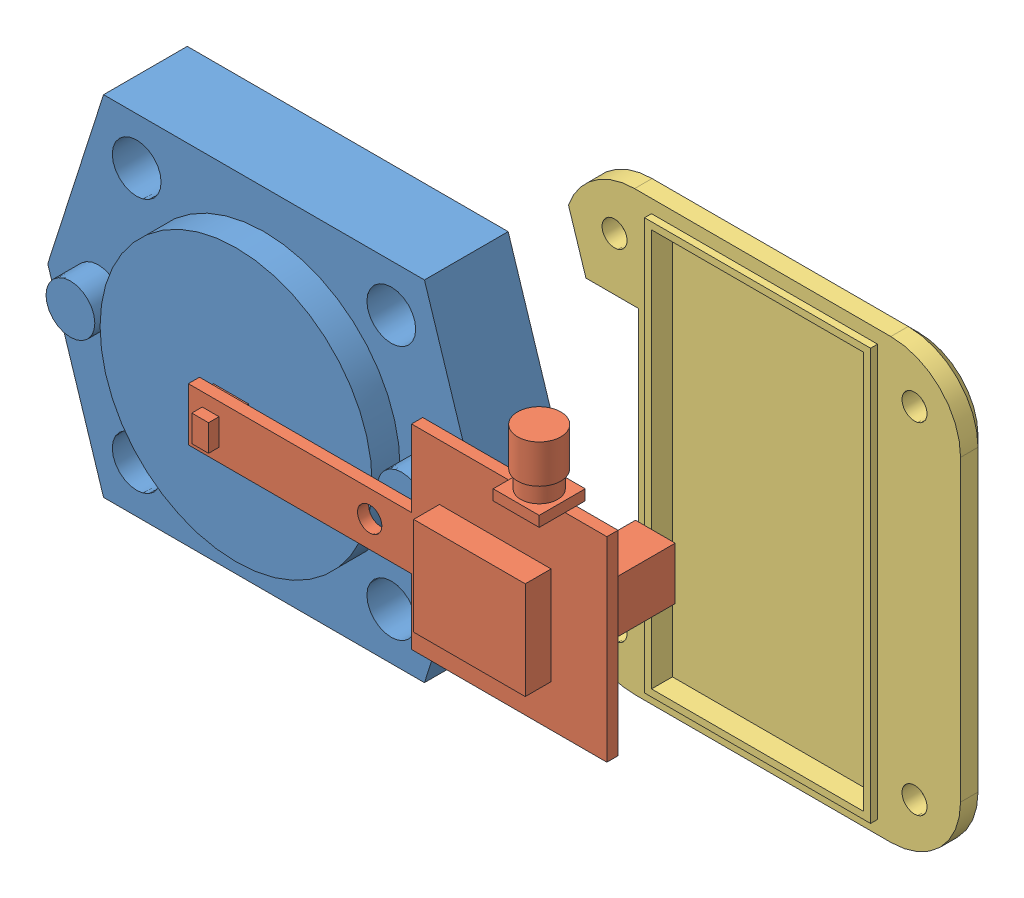
SolidWorks assembly sensor_asm, configuration Default. Lengths in mm.
Overall size (110.85 62.8 36.3).
6 component instances, 4 part files, 4 mates.
Components (placement in the parent):
- indicador-1: indicador [Default] at origin size (62 50 16)
- pcb-1: pcb [Default] at (29.75 0 19) size (60 37.5 14.8)
- case_bat_r1-2: case_bat_r1 [Default] at origin size (112.95 62.8 38.44)
- battery_holder-1: battery_holder [Default] at (63.8862 0 14.3617) x (-1 0 0) z (0 0 -1) size (57 32.01 15) (hidden)
- battery_holder-4: battery_holder [Default] at (51.5841 0 6.2) x (0 -1 0) z (0 0 -1) size (57 32.01 15) (hidden)
- battery_holder-5: battery_holder [Default] at (61.9432 0 8.3992) x (0 -1 0) z (1 0 0) size (57 32.01 15) (hidden)
Mates (geometry in assembly coordinates):
- Concentric1: concentric: cylinder of indicador-1 through (23.75 0 16) axis (0 0 -1) radius 3.5; cylinder of pcb-1 through (23.75 0 20.6) axis (0 0 -1) radius 1.75
- Distance1: distance = 3 mm: plane of pcb-1 through (29.75 0 19) normal (0 0 -1); plane of indicador-1 through (0 0 16) normal (0 0 1)
- Coincident1: coincident: plane of case_bat_r1-2 through (0 0 8) normal (0 0 -1); plane of battery_holder-4 through (37.0841 27 8) normal (0 0 1)
- Width1: width: plane of battery_holder-4 through (66.0841 -28.5 8) normal (0 -1 0); plane of battery_holder-4 through (37.0841 28.5 8) normal (0 1 0); plane of case_bat_r1-2 through (29.75 18.4 7) normal (0 1 0); plane of case_bat_r1-2 through (59.85 -18.4 7) normal (0 -1 0)
